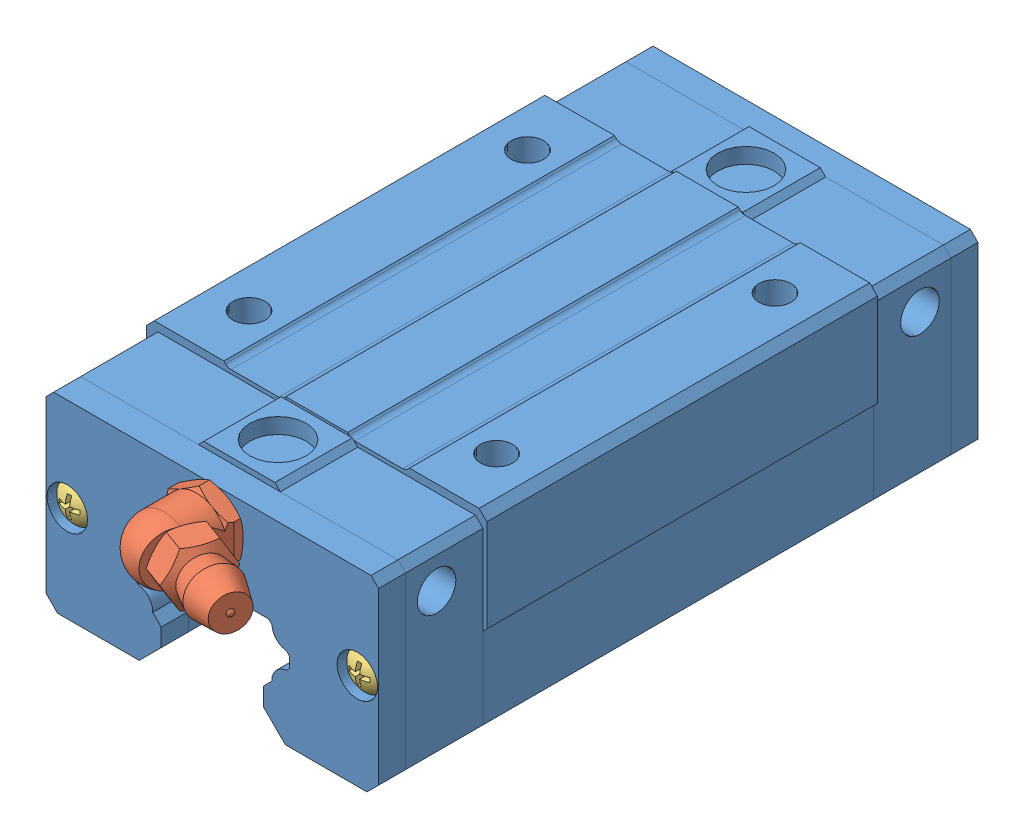
SolidWorks assembly HGH20CAZ0C, configuration Default. Lengths in mm.
Overall size (44 25.5 89.06).
6 component instances, 3 part files, 7 mates.
Components (placement in the parent):
- HGH20CAZ0C, BLOCK, MIDSECTION-1: HGH20CAZ0C, BLOCK, MIDSECTION [Default] at origin size (44 25.5 77.5)
- HGH20CAZ0C, BLOCK OIL FILLING PART-1: HGH20CAZ0C, BLOCK OIL FILLING PART [Default] at (0 11 33.75) x (0 0 -1) z (0 1 0) size (16.4 16.42 9.24)
- HGH20CAZ0C, SCREW HEAD-1: HGH20CAZ0C, SCREW HEAD [Default] at (18.75 2.9 36.65) x (0 0 1) z (-1 0 0) size (2.26 5 5)
- HGH20CAZ0C, SCREW HEAD-2: HGH20CAZ0C, SCREW HEAD [Default] at (-18.75 2.9 36.65) x (0 0 1) z (-1 0 0) size (2.26 5 5)
- HGH20CAZ0C, SCREW HEAD-3: HGH20CAZ0C, SCREW HEAD [Default] at (18.75 2.9 -36.65) x (0 0 -1) z (1 0 0) size (2.26 5 5)
- HGH20CAZ0C, SCREW HEAD-4: HGH20CAZ0C, SCREW HEAD [Default] at (-18.75 2.9 -36.65) x (0 0 -1) z (1 0 0) size (2.26 5 5)
Mates (geometry in assembly coordinates):
- Coincident2: coordinate: point of assembly; point of HGH20CAZ0C, BLOCK, MIDSECTION-1; point of assembly
- Coincident3: coincident: plane of assembly; plane of assembly; plane of HGH20CAZ0C, BLOCK, MIDSECTION-1 through (-9.8292 -3.1926 38.75) normal (0 0 1); plane of HGH20CAZ0C, BLOCK OIL FILLING PART-1 through (0 7.5 38.75) normal (0 0 -1)
- Concentric1: concentric: cylinder of assembly; cylinder of assembly; cylinder of HGH20CAZ0C, BLOCK, MIDSECTION-1 through (0 11 34.75) axis (0 0 1) radius 3; cylinder of HGH20CAZ0C, BLOCK OIL FILLING PART-1 through (0 11 36.48) axis (0 0 1) radius 3
- Parallel1: parallel: plane of assembly through (0 0 0) normal (0 1 0); plane of HGH20CAZ0C, BLOCK OIL FILLING PART-1 through (0 11 33.75) normal (0 1 0); plane of assembly
- Coincident4: coincident: plane of assembly; plane of assembly; plane of HGH20CAZ0C, BLOCK, MIDSECTION-1 through (18.75 2.9 36.65) normal (0 0 1); plane of HGH20CAZ0C, SCREW HEAD-1 through (17.5 2.9 36.65) normal (0 0 -1)
- Concentric2: concentric: cylinder of assembly; cone of assembly; cylinder of HGH20CAZ0C, BLOCK, MIDSECTION-1 through (18.75 2.9 36.65) axis (0 0 1) radius 2.625; cone of HGH20CAZ0C, SCREW HEAD-1 through (18.75 2.9 36.65) axis (0 0 1)
- Parallel2: parallel: plane of assembly through (0 0 0) normal (1 0 0); plane of HGH20CAZ0C, SCREW HEAD-1 through (18.75 2.9 36.65) normal (-1 0 0); plane of assembly
